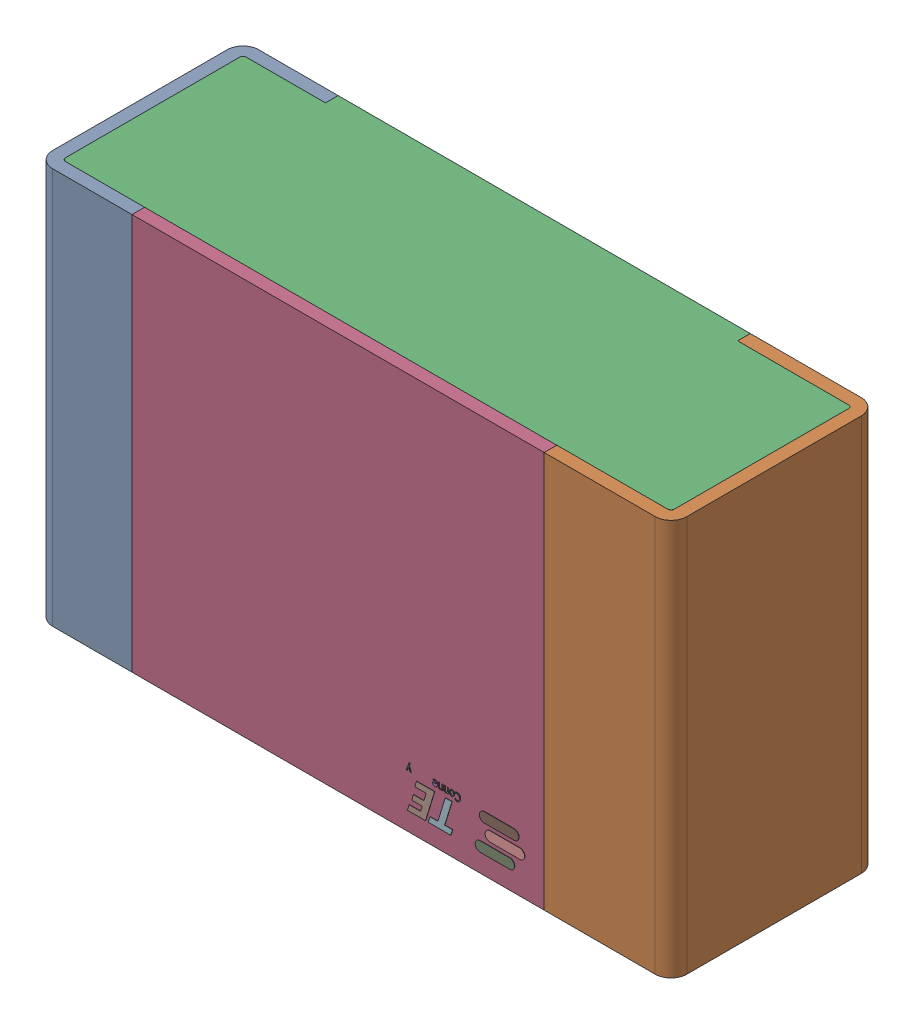
SolidWorks assembly RLH2.step, configuration Default. Lengths in mm.
Overall size (2 1.25 0.65).
5 component instances, 4 part files, 0 mates.
Components (placement in the parent):
- Res_TE_Connectivity_CPF0805B66R5E1_eec.step-1: Res_TE_Connectivity_CPF0805B66R5E1_eec.step [Default] at (5.191 24.257 0) x (-1 0 0) z (0 0 1) size (2 1.25 0.65)
  - 1.step-1: 1.step [Default] at origin size (2 1.25 0.65)
  - 2.step-1: 2.step [Default] at origin size (1.92 1.25 0.61)
  - 3.step-1: 3.step [Default] at origin size (1.3 1.25 0.04)
  - TE connectivity Logo 1 (2).step-1: TE connectivity Logo 1 (2).step [Default] at (5.4285 0.313 0.551) x (-1 0 0) z (0 0 1) size (0.37 0.13 0.11)
